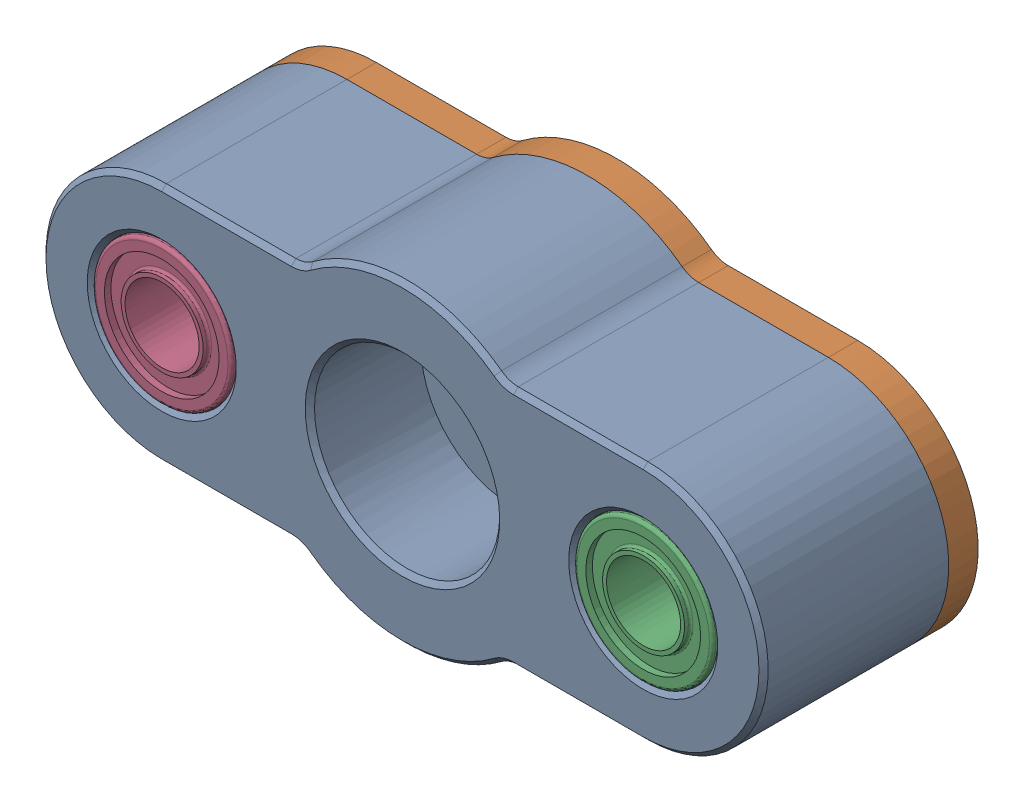
SolidWorks assembly SSDCT Spring End Asmbly_1, configuration Default. Lengths in mm.
Overall size (78 34 23.29).
13 component instances, 6 part files, 0 mates.
Components (placement in the parent):
- SSDCT Spring End Base-1: SSDCT Spring End Base [Default] at origin size (78 34 20)
- SSDCT Spring End Plate-1: SSDCT Spring End Plate [Default] at origin size (78 34 3.17)
- LM8SUU-1: LM8SUU [Default] at (26 0 94.675) x (0 0 -1) z (1 0 0) size (17 15 15)
- LM8SUU-2: LM8SUU [Default] at (-26 0 94.675) x (0 0 -1) z (1 0 0) size (17 15 15)
- 6659K677-1: 6659K677 [Default] at (0 0 83.175) size (16 16 8)
- 94180A333-1: 94180A333 [Default] at (-13 7.5 83.175) x (1 0 0) z (0 0 -1) size (5.56 5.56 6.4)
- 94180A333-2: 94180A333 [Default] at (-13 -7.5 83.175) x (1 0 0) z (0 0 -1) size (5.56 5.56 6.4)
- 94180A333-3: 94180A333 [Default] at (13 -7.5 83.175) x (1 0 0) z (0 0 -1) size (5.56 5.56 6.4)
- 94180A333-4: 94180A333 [Default] at (13 7.5 83.175) x (1 0 0) z (0 0 -1) size (5.56 5.56 6.4)
- M3 x 0.5 mm 14mm Length Hex Drive Flat Head Screw-1: M3 x 0.5 mm 14mm Length Hex Drive Flat Head Screw [Default] at (-13 7.5 80) x (1 0 0) z (0 0 -1) size (6 6 14.12)
- M3 x 0.5 mm 14mm Length Hex Drive Flat Head Screw-2: M3 x 0.5 mm 14mm Length Hex Drive Flat Head Screw [Default] at (-13 -7.5 80) x (1 0 0) z (0 0 -1) size (6 6 14.12)
- M3 x 0.5 mm 14mm Length Hex Drive Flat Head Screw-3: M3 x 0.5 mm 14mm Length Hex Drive Flat Head Screw [Default] at (13 -7.5 80) x (1 0 0) z (0 0 -1) size (6 6 14.12)
- M3 x 0.5 mm 14mm Length Hex Drive Flat Head Screw-4: M3 x 0.5 mm 14mm Length Hex Drive Flat Head Screw [Default] at (13 7.5 80) x (1 0 0) z (0 0 -1) size (6 6 14.12)
